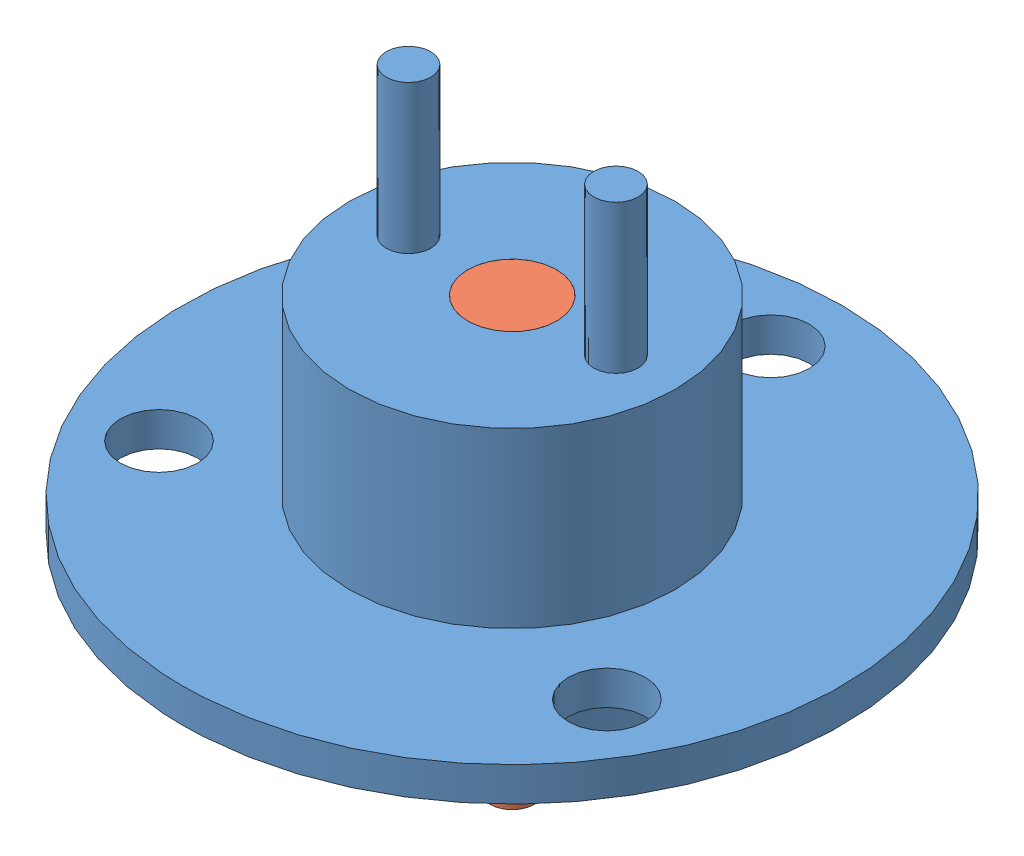
SolidWorks assembly Ensamblaje1, configuration Predeterminado. Lengths in mm.
Overall size (44.5 39 44.5).
2 component instances, 2 part files, 2 mates.
Components (placement in the parent):
- Chasis-1: Chasis [Predeterminado] at (0.6444 -16.3871 44.5) size (44.5 29 44.5)
- eje-1: eje [Predeterminado] at (0.6444 2.6129 44.5) x (0.965153 0 -0.261687) z (0 -1 0) size (6 6 29)
Mates (geometry in assembly coordinates):
- Coincidente1: coincident aligned: plane of Chasis-1 through (0.6444 2.6129 44.5) normal (0 1 0); plane of eje-1 through (0.6444 2.6129 44.5) normal (0 1 0)
- Concéntrica1: concentric aligned: cylinder of Chasis-1 through (0.6444 -24.6871 44.5) axis (0 1 0) radius 3; cylinder of eje-1 through (0.6444 -16.3871 44.5) axis (0 1 0) radius 3
